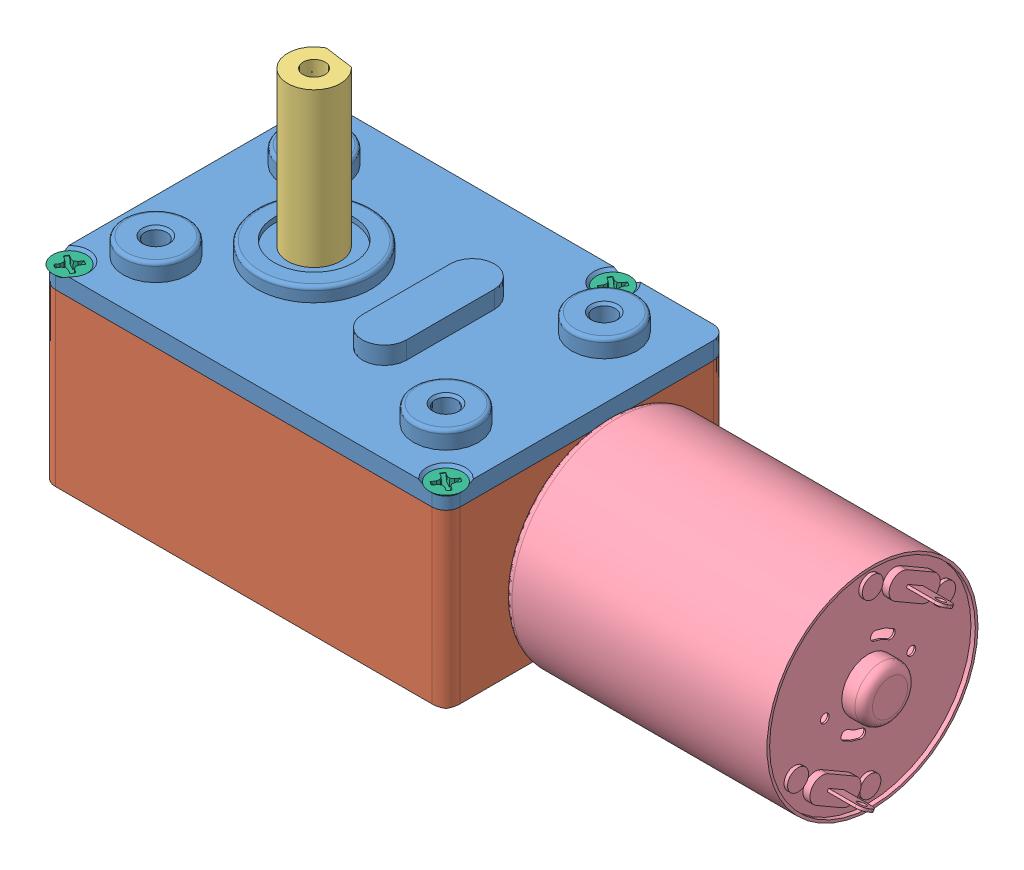
SolidWorks assembly Chihai CHW-GW4632-370, DC Worm Gear Motor, 6 V, 6 RPM, configuration Default. Lengths in mm.
Overall size (81.23 43.7 34.06).
10 component instances, 6 part files, 15 mates.
Components (placement in the parent):
- Cover, Chihai CHW-GW4632-370, DC Worm Gear Motor, 6 V, 6 RPM-1: Cover, Chihai CHW-GW4632-370, DC Worm Gear Motor, 6 V, 6 RPM [Default] at origin size (46 21.6 32)
- Gear Body, Chihai CHW-GW4632-370, DC Worm Gear Motor, 6 V, 6 RPM-1: Gear Body, Chihai CHW-GW4632-370, DC Worm Gear Motor, 6 V, 6 RPM [Default] at (-1 0 0) size (46 21.1 32)
- Shaft, Chihai CHW-GW4632-370, DC Worm Gear Motor, 6 V, 6 RPM-1: Shaft, Chihai CHW-GW4632-370, DC Worm Gear Motor, 6 V, 6 RPM [Default] x (0.134746 0 -0.99088) z (0.99088 0 0.134746) size (6 30.5 6)
- DC Motor, Chihai CHW-GW4632-370, DC Worm Gear Motor, 6 V, 6 RPM-1: DC Motor, Chihai CHW-GW4632-370, DC Worm Gear Motor, 6 V, 6 RPM [Default] at (61 -11.2 -2.5) size (44.2 24 24) (flexible)
  - DC Motor Body, Chihai CHW-GW4632-370, DC Worm Gear Motor, 6 V, 6 RPM-1: DC Motor Body, Chihai CHW-GW4632-370, DC Worm Gear Motor, 6 V, 6 RPM [Default] at origin size (34.2 24 24)
  - DC Motor Shaft, Chihai CHW-GW4632-370, DC Worm Gear Motor, 6 V, 6 RPM-1: DC Motor Shaft, Chihai CHW-GW4632-370, DC Worm Gear Motor, 6 V, 6 RPM [Default] at (-20 0 0) x (1 0 0) z (0 0.450234 0.89291) size (40 2 2)
- M2 X 6 SS Flat Head Screw, Chihai CHW-GW4632-370, DC Worm Gear Motor, 6 V, 6 RPM-1: M2 X 6 SS Flat Head Screw, Chihai CHW-GW4632-370, DC Worm Gear Motor, 6 V, 6 RPM [default] at (29.4 0.5 14.4) x (-0.837169 0 -0.546944) z (0 1 0) size (3.8 3.8 7.68)
- M2 X 6 SS Flat Head Screw, Chihai CHW-GW4632-370, DC Worm Gear Motor, 6 V, 6 RPM-2: M2 X 6 SS Flat Head Screw, Chihai CHW-GW4632-370, DC Worm Gear Motor, 6 V, 6 RPM [default] at (-13.4 0.5 14.4) x (-0.837169 0 -0.546944) z (0 1 0) size (3.8 3.8 7.68)
- M2 X 6 SS Flat Head Screw, Chihai CHW-GW4632-370, DC Worm Gear Motor, 6 V, 6 RPM-3: M2 X 6 SS Flat Head Screw, Chihai CHW-GW4632-370, DC Worm Gear Motor, 6 V, 6 RPM [default] at (-13.4 0.5 -14.4) x (-0.837169 0 -0.546944) z (0 1 0) size (3.8 3.8 7.68)
- M2 X 6 SS Flat Head Screw, Chihai CHW-GW4632-370, DC Worm Gear Motor, 6 V, 6 RPM-4: M2 X 6 SS Flat Head Screw, Chihai CHW-GW4632-370, DC Worm Gear Motor, 6 V, 6 RPM [default] at (19.6 0.5 -14.4) x (-0.837169 0 -0.546944) z (0 1 0) size (3.8 3.8 7.68)
Mates (geometry in assembly coordinates):
- Coincident1: coordinate: point of Cover, Chihai CHW-GW4632-370, DC Worm Gear Motor, 6 V, 6 RPM-1
- Coincident2: coincident anti-aligned: plane of Cover, Chihai CHW-GW4632-370, DC Worm Gear Motor, 6 V, 6 RPM-1 through (0 0 0) normal (0 -1 0); plane of Gear Body, Chihai CHW-GW4632-370, DC Worm Gear Motor, 6 V, 6 RPM-1 through (-1 0 0) normal (0 1 0)
- Coincident3: coincident aligned: plane of Cover, Chihai CHW-GW4632-370, DC Worm Gear Motor, 6 V, 6 RPM-1 through (0 0 0) normal (0 1 0); plane of Shaft, Chihai CHW-GW4632-370, DC Worm Gear Motor, 6 V, 6 RPM-1 through (0 0 0) normal (0 1 0)
- Concentric3: concentric anti-aligned: cylinder of Cover, Chihai CHW-GW4632-370, DC Worm Gear Motor, 6 V, 6 RPM-1 through (0 3 0) axis (0 -1 0) radius 3; cylinder of Shaft, Chihai CHW-GW4632-370, DC Worm Gear Motor, 6 V, 6 RPM-1 through (0 -10 0) axis (0 1 0) radius 3
- Concentric4: concentric anti-aligned: cylinder of Gear Body, Chihai CHW-GW4632-370, DC Worm Gear Motor, 6 V, 6 RPM-1 through (-15 -11.2 -2.5) axis (1 0 0) radius 3; cylinder of DC Motor, Chihai CHW-GW4632-370, DC Worm Gear Motor, 6 V, 6 RPM-1/DC Motor Shaft, Chihai CHW-GW4632-370, DC Worm Gear Motor, 6 V, 6 RPM-1 through (61 -11.2 -2.5) axis (-1 0 0) radius 1
- Coincident4: coincident anti-aligned: plane of Gear Body, Chihai CHW-GW4632-370, DC Worm Gear Motor, 6 V, 6 RPM-1 through (31 -20.6 -16) normal (1 0 0); plane of DC Motor, Chihai CHW-GW4632-370, DC Worm Gear Motor, 6 V, 6 RPM-1/DC Motor Body, Chihai CHW-GW4632-370, DC Worm Gear Motor, 6 V, 6 RPM-1 through (31 -11.2 -2.5) normal (-1 0 0)
- Parallel1: parallel aligned: plane of DC Motor, Chihai CHW-GW4632-370, DC Worm Gear Motor, 6 V, 6 RPM-1 through (61 -11.2 -2.5) normal (0 0 1); plane of assembly through (0 0 0) normal (0 0 1)
- Concentric5: concentric aligned: cylinder of Cover, Chihai CHW-GW4632-370, DC Worm Gear Motor, 6 V, 6 RPM-1 through (29.4 2 14.4) axis (0 1 0) radius 1.1; cylinder of M2 X 6 SS Flat Head Screw, Chihai CHW-GW4632-370, DC Worm Gear Motor, 6 V, 6 RPM-1 through (29.4 1.7 14.4) axis (0 1 0) radius 1
- Coincident11: coincident aligned: cone of Cover, Chihai CHW-GW4632-370, DC Worm Gear Motor, 6 V, 6 RPM-1 through (29.4 2 14.4) axis (0 -1 0); cone of M2 X 6 SS Flat Head Screw, Chihai CHW-GW4632-370, DC Worm Gear Motor, 6 V, 6 RPM-1 through (29.4 1.7 14.4) axis (0 -1 0)
- Concentric6: concentric aligned: cylinder of Gear Body, Chihai CHW-GW4632-370, DC Worm Gear Motor, 6 V, 6 RPM-1 through (-13.4 0 14.4) axis (0 1 0) radius 0.8; cylinder of M2 X 6 SS Flat Head Screw, Chihai CHW-GW4632-370, DC Worm Gear Motor, 6 V, 6 RPM-2 through (-13.4 1.7 14.4) axis (0 1 0) radius 1
- Coincident12: coincident aligned: cone of Cover, Chihai CHW-GW4632-370, DC Worm Gear Motor, 6 V, 6 RPM-1 through (-13.4 2 14.4) axis (0 -1 0); cone of M2 X 6 SS Flat Head Screw, Chihai CHW-GW4632-370, DC Worm Gear Motor, 6 V, 6 RPM-2 through (-13.4 1.7 14.4) axis (0 -1 0)
- Concentric7: concentric aligned: cylinder of Gear Body, Chihai CHW-GW4632-370, DC Worm Gear Motor, 6 V, 6 RPM-1 through (-13.4 0 -14.4) axis (0 1 0) radius 0.8; cylinder of M2 X 6 SS Flat Head Screw, Chihai CHW-GW4632-370, DC Worm Gear Motor, 6 V, 6 RPM-3 through (-13.4 1.7 -14.4) axis (0 1 0) radius 1
- Coincident13: coincident aligned: cone of Cover, Chihai CHW-GW4632-370, DC Worm Gear Motor, 6 V, 6 RPM-1 through (-13.4 2 -14.4) axis (0 -1 0); cone of M2 X 6 SS Flat Head Screw, Chihai CHW-GW4632-370, DC Worm Gear Motor, 6 V, 6 RPM-3 through (-13.4 1.7 -14.4) axis (0 -1 0)
- Concentric8: concentric aligned: cylinder of Gear Body, Chihai CHW-GW4632-370, DC Worm Gear Motor, 6 V, 6 RPM-1 through (19.6 0 -14.4) axis (0 1 0) radius 0.8; cylinder of M2 X 6 SS Flat Head Screw, Chihai CHW-GW4632-370, DC Worm Gear Motor, 6 V, 6 RPM-4 through (19.6 1.7 -14.4) axis (0 1 0) radius 1
- Coincident14: coincident aligned: cone of Cover, Chihai CHW-GW4632-370, DC Worm Gear Motor, 6 V, 6 RPM-1 through (19.6 2 -14.4) axis (0 -1 0); cone of M2 X 6 SS Flat Head Screw, Chihai CHW-GW4632-370, DC Worm Gear Motor, 6 V, 6 RPM-4 through (19.6 1.7 -14.4) axis (0 -1 0)
